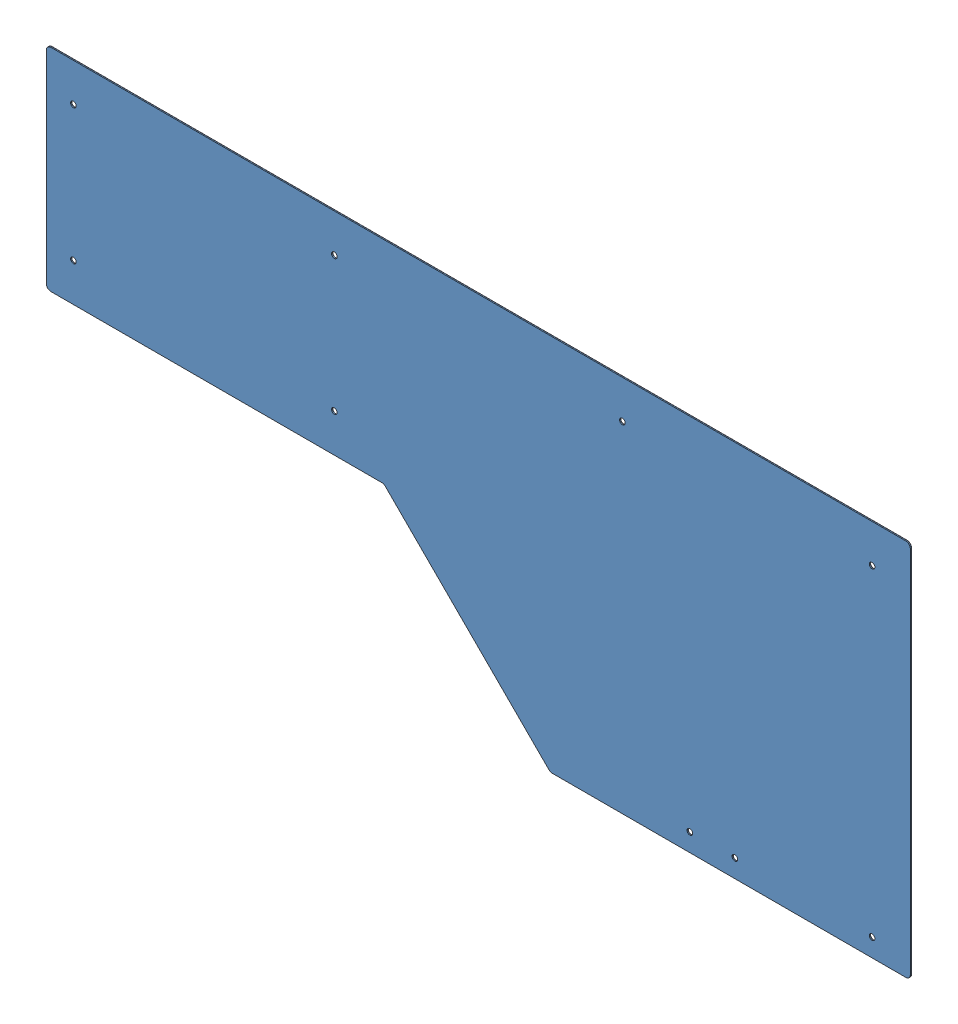
SolidWorks assembly GE-20041, configuration GE-20041-Left. Lengths in mm.
Overall size (1219.2 533.4 1.84).
2 component instances, 2 part files, 9 mates.
Components (placement in the parent):
- GE-20040-1: GE-20040 [Default] x (1 0 0) z (0 -1 0) size (1219.2 1.59 533.4)
- GE-20041-Vinyl-1: GE-20041-Vinyl [GE-20041-Left-Vinyl] at (0 0 -0.254) x (1 0 0) z (0 -1 0) size (1219.2 0.25 533.4)
Mates (geometry in assembly coordinates):
- Coincident1: coincident anti-aligned: plane of GE-20040-1 through (-505.3697 6.35 0) normal (0 0 -1)
- Coincident2: coincident anti-aligned: plane of GE-20040-1 through (-505.3697 0 1.5875) normal (0 -1 0)
- Coincident3: coincident aligned: plane of GE-20040-1 through (0 0 1.5875) normal (1 0 0)
- Coincident4: coincident anti-aligned: plane of GE-20040-1 through (-505.3697 6.35 0) normal (0 0 -1); plane of GE-20041-Vinyl-1 through (-1219.2 0 0) normal (0 0 1)
- Coincident5: coincident aligned: plane of GE-20040-1 through (0 0 1.5875) normal (1 0 0); plane of GE-20041-Vinyl-1 through (0 0 1.3335) normal (1 0 0)
- Coincident6: coincident aligned: plane of GE-20040-1 through (-505.3697 0 1.5875) normal (0 -1 0); plane of GE-20041-Vinyl-1 through (-505.3697 0 1.3335) normal (0 -1 0)
- Coincident7: coincident: plane of GE-20040-1 through (-493.774 3.175 3.175) normal (0 0 1); plane of GE-20041-Vinyl-1 through (-493.774 3.175 3.175) normal (0 0 -1)
- Coincident8: coincident: plane of GE-20040-1 through (0 0 3.175) normal (1 0 0); plane of GE-20041-Vinyl-1 through (0 0 6.35) normal (1 0 0)
- Coincident9: coincident aligned: plane of GE-20040-1 through (-1219.2 533.4 3.175) normal (0 1 0); plane of GE-20041-Vinyl-1 through (-1219.2 533.4 6.35) normal (0 1 0)
